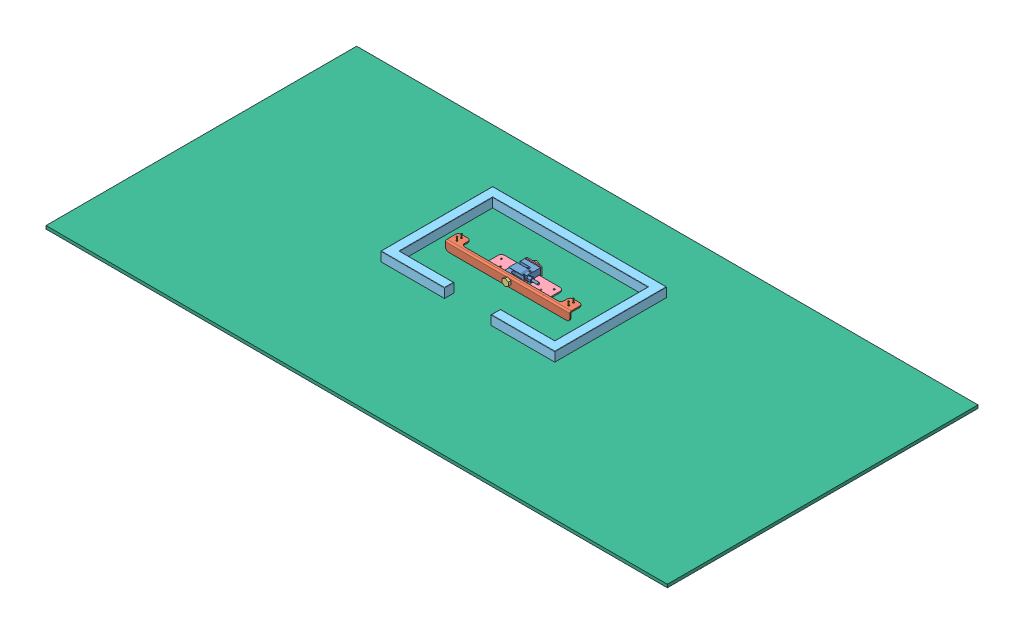
SolidWorks assembly WallBench - Assembly, configuration Default. Lengths in mm.
Overall size (2000 68.76 1000).
19 component instances, 9 part files, 39 mates.
Components (placement in the parent):
- WallBench - Galga-1: WallBench - Galga [Default] at (16.3505 77.3571 24.2126) size (82.8 24.7 76.5)
- WallBench - L Support-1: WallBench - L Support [Default] at (16.3505 104.6071 62.4626) x (1 0 0) z (0 1 0) size (400 41.44 29.24)
- Tornillo_M12-1: Tornillo_M12 [Default] at (16.3505 86.8571 -26.0374) x (0.845145 -0.534536 0) z (-0.534536 -0.845145 0) size (23.08 23 20.45)
- WallBench - Main Support-1: WallBench - Main Support [Default] at (16.3505 73.8571 24.1992) size (200 29.84 79.74)
- Tornillo_M12-2: Tornillo_M12 [Default] at (16.3505 86.8571 74.4626) x (0.885495 -0.464649 0) z (0.464649 0.885495 0) size (23.08 23 20.45)
- WallBench - Frame-1: WallBench - Frame [Default] at (21.3853 69.8571 19.8119) x (1 0 0) z (0 1 0) size (560 360 30)
- WallBench - Moving wall-1: WallBench - Moving wall [Default] at (20.7705 101.0937 20.8295) size (495 10 295) (hidden)
- Fingerboard-1: Fingerboard [Default] at (-181.7295 131.0937 22.8295) x (1 0 0) z (0 1 0) size (400 99 40) (hidden)
- Wall-1: Wall [Default] at (101.6517 59.8571 137.8054) size (2000 10 1000)
- din95_2_5x30_st-2: din95_2_5x30_st [Default] at (-68.6495 74.423 46.6992) x (-0.635709 0 -0.771929) z (0 -1 0) size (4.66 4.7 30.59)
- din95_2_5x30_st-3: din95_2_5x30_st [Default] at (-68.6495 74.423 1.6992) x (-0.635709 0 -0.771929) z (0 -1 0) size (4.66 4.7 30.59)
- din95_2_5x30_st-4: din95_2_5x30_st [Default] at (-48.6495 74.423 24.1992) x (-0.635709 0 -0.771929) z (0 -1 0) size (4.66 4.7 30.59)
- din95_2_5x30_st-5: din95_2_5x30_st [Default] at (101.3505 74.423 1.6992) x (-0.635709 0 -0.771929) z (0 -1 0) size (4.66 4.7 30.59)
- din95_2_5x30_st-6: din95_2_5x30_st [Default] at (81.3505 74.423 24.1992) x (-0.635709 0 -0.771929) z (0 -1 0) size (4.66 4.7 30.59)
- din95_2_5x30_st-7: din95_2_5x30_st [Default] at (101.3505 74.423 46.6992) x (-0.635709 0 -0.771929) z (0 -1 0) size (4.66 4.7 30.59)
- din95_2_5x30_st-8: din95_2_5x30_st [Default] at (196.3505 112.5937 35.0246) x (-0.899744 0 -0.436419) z (0 -1 0) size (4.66 4.7 30.59)
- din95_2_5x30_st-9: din95_2_5x30_st [Default] at (196.3505 112.5937 50.0246) x (-0.880156 0 0.474684) z (0 -1 0) size (4.66 4.7 30.59)
- din95_2_5x30_st-10: din95_2_5x30_st [Default] at (-163.6495 112.5937 35.0246) x (-0.080853 0 -0.996726) z (0 -1 0) size (4.66 4.7 30.59)
- din95_2_5x30_st-11: din95_2_5x30_st [Default] at (-163.6495 112.5937 50.0246) x (-0.159022 0 -0.987275) z (0 -1 0) size (4.66 4.7 30.59)
Mates (geometry in assembly coordinates):
- Concéntrica1: concentric anti-aligned: cylinder of WallBench - Galga-1 through (16.3505 86.8571 62.4636) axis (0 0 -1) radius 5; cylinder of WallBench - Main Support-1 through (16.3505 86.8571 -18.0384) axis (0 0 1) radius 7
- Coincidente2: coincident anti-aligned: plane of WallBench - Galga-1 through (-9.0495 96.3571 -14.0374) normal (0 0 -1); plane of WallBench - Main Support-1 through (-4.6495 94.695 -14.0374) normal (0 0 1)
- Concéntrica4: concentric aligned: cylinder of WallBench - Galga-1 through (16.3505 86.8571 62.4636) axis (0 0 -1) radius 5; cylinder of Tornillo_M12-1 through (16.3505 86.8571 -3.0374) axis (0 0 -1) radius 6
- Coincidente3: coincident anti-aligned: plane of Tornillo_M12-1 through (16.3505 86.8571 -18.0374) normal (0 0 1); plane of WallBench - Main Support-1 through (-4.6495 94.695 -18.0374) normal (0 0 -1)
- Perpendicular1: perpendicular: plane of Tornillo_M12-1 through (26.3505 81.0836 -18.0374) normal (1 0 0); plane of WallBench - Main Support-1 through (-4.6495 99.695 -18.0374) normal (0 1 0)
- Concéntrica5: concentric anti-aligned: cylinder of WallBench - Galga-1 through (16.3505 86.8571 -14.0384) axis (0 0 1) radius 5; cylinder of WallBench - L Support-1 through (16.3505 86.8571 72.4626) axis (0 0 -1) radius 7
- Coincidente4: coincident anti-aligned: plane of WallBench - Galga-1 through (-9.0495 96.3571 62.4626) normal (0 0 1); plane of WallBench - L Support-1 through (-173.6495 127.3571 62.4626) normal (0 0 -1)
- Paralelo1: parallel anti-aligned: plane of WallBench - Galga-1 through (10.7505 96.3571 42.4626) normal (0 1 0); plane of WallBench - L Support-1 through (-173.6495 97.0937 35.0246) normal (0 -1 0)
- Concéntrica7: concentric aligned: cylinder of WallBench - Galga-1 through (16.3505 86.8571 -14.0384) axis (0 0 1) radius 5; cylinder of Tornillo_M12-2 through (16.3505 86.8571 51.4626) axis (0 0 1) radius 6
- Coincidente6: coincident anti-aligned: plane of WallBench - L Support-1 through (-173.6495 127.3571 66.4626) normal (0 0 1); plane of Tornillo_M12-2 through (16.3505 86.8571 66.4626) normal (0 0 -1)
- Perpendicular2: perpendicular: plane of WallBench - L Support-1 through (-173.6495 101.0937 35.0246) normal (0 1 0); plane of Tornillo_M12-2 through (6.3505 81.0836 66.4626) normal (-1 0 0)
- Coincidente9: coincident anti-aligned: plane of WallBench - Frame-1 through (21.3853 69.8571 19.8119) normal (0 -1 0); plane of Wall-1 through (101.6517 69.8571 137.8054) normal (0 1 0)
- Coincidente13: coincident anti-aligned: plane of WallBench - Main Support-1 through (-4.6495 69.8571 -37.7008) normal (0 -1 0); plane of Wall-1 through (101.6517 69.8571 137.8054) normal (0 1 0)
- Paralelo5: parallel anti-aligned: plane of WallBench - L Support-1 through (-173.6495 127.3571 66.4626) normal (0 0 1); plane of WallBench - Frame-1 through (-228.6147 99.8571 169.8119) normal (0 0 -1)
- Coincidente15: coincident anti-aligned: plane of WallBench - Moving wall-1 through (20.7705 111.0937 20.8295) normal (0 1 0); plane of Fingerboard-1 through (218.2705 111.0937 72.3295) normal (0 -1 0)
- Distancia1: distance = 45 mm aligned: plane of Fingerboard-1 through (-181.7295 141.0937 -16.6705) normal (-1 0 0); plane of WallBench - Moving wall-1 through (-226.7295 111.0937 -126.6705) normal (-1 0 0)
- Distancia2: distance = 100 mm: plane of Fingerboard-1 through (218.2705 111.0937 -26.6705) normal (0 0 -1); line of WallBench - Moving wall-1 through (268.2705 101.0937 -126.6705) axis (-1 0 0)
- Coincidente19: coincident anti-aligned: plane of WallBench - L Support-1 through (-173.6495 101.0937 35.0246) normal (0 1 0); plane of WallBench - Moving wall-1 through (20.7705 101.0937 20.8295) normal (0 -1 0)
- Paralelo6: parallel aligned: plane of WallBench - Galga-1 through (10.7505 96.3571 42.4626) normal (0 1 0); plane of WallBench - Main Support-1 through (-4.6495 73.8571 -37.7008) normal (0 1 0)
- Concéntrica9: concentric aligned: cylinder of WallBench - Main Support-1 through (-68.6495 69.8561 1.6992) axis (0 1 0) radius 2.5; cylinder of din95_2_5x30_st-3 through (-68.6495 67.073 1.6992) axis (0 1 0) radius 1.25
- Concéntrica10: concentric aligned: cylinder of WallBench - Main Support-1 through (-48.6495 69.8561 24.1992) axis (0 1 0) radius 2.5; cylinder of din95_2_5x30_st-4 through (-48.6495 67.073 24.1992) axis (0 1 0) radius 1.25
- Concéntrica11: concentric aligned: cylinder of WallBench - Main Support-1 through (-68.6495 69.8561 46.6992) axis (0 1 0) radius 2.5; cylinder of din95_2_5x30_st-2 through (-68.6495 67.073 46.6992) axis (0 1 0) radius 1.25
- Concéntrica12: concentric aligned: cylinder of WallBench - Main Support-1 through (101.3505 69.8561 1.6992) axis (0 1 0) radius 2.5; cylinder of din95_2_5x30_st-5 through (101.3505 67.073 1.6992) axis (0 1 0) radius 1.25
- Concéntrica13: concentric aligned: cylinder of WallBench - Main Support-1 through (81.3505 69.8561 24.1992) axis (0 1 0) radius 2.5; cylinder of din95_2_5x30_st-6 through (81.3505 67.073 24.1992) axis (0 1 0) radius 1.25
- Concéntrica14: concentric aligned: cylinder of WallBench - Main Support-1 through (101.3505 69.8561 46.6992) axis (0 1 0) radius 2.5; cylinder of din95_2_5x30_st-7 through (101.3505 67.073 46.6992) axis (0 1 0) radius 1.25
- Coincidente22: coincident: circle of WallBench - Main Support-1; cone of din95_2_5x30_st-3 through (-68.6495 72.998 1.6992) axis (0 -1 0)
- Coincidente23: coincident: circle of WallBench - Main Support-1; cone of din95_2_5x30_st-4 through (-48.6495 72.998 24.1992) axis (0 -1 0); plane of ?
- Coincidente24: coincident: circle of WallBench - Main Support-1; cone of din95_2_5x30_st-2 through (-68.6495 72.998 46.6992) axis (0 -1 0); plane of ?
- Coincidente25: coincident: circle of WallBench - Main Support-1; cone of din95_2_5x30_st-7 through (101.3505 72.998 46.6992) axis (0 -1 0); plane of ?
- Coincidente26: coincident: circle of WallBench - Main Support-1; cone of din95_2_5x30_st-6 through (81.3505 72.998 24.1992) axis (0 -1 0); plane of ?
- Coincidente27: coincident: circle of WallBench - Main Support-1; cone of din95_2_5x30_st-5 through (101.3505 72.998 1.6992) axis (0 -1 0); plane of ?
- Concéntrica15: concentric anti-aligned: cylinder of WallBench - L Support-1 through (196.3505 101.0947 50.0246) axis (0 -1 0) radius 2.5; cylinder of din95_2_5x30_st-9 through (196.3505 105.2437 50.0246) axis (0 1 0) radius 1.25
- Concéntrica16: concentric anti-aligned: cylinder of WallBench - L Support-1 through (196.3505 101.0947 35.0246) axis (0 -1 0) radius 2.5; cylinder of din95_2_5x30_st-8 through (196.3505 105.2437 35.0246) axis (0 1 0) radius 1.25
- Concéntrica17: concentric anti-aligned: cylinder of WallBench - L Support-1 through (-163.6495 101.0947 35.0246) axis (0 -1 0) radius 2.5; cylinder of din95_2_5x30_st-10 through (-163.6495 105.2437 35.0246) axis (0 1 0) radius 1.25
- Concéntrica18: concentric anti-aligned: cylinder of WallBench - L Support-1 through (-163.6495 101.0947 50.0246) axis (0 -1 0) radius 2.5; cylinder of din95_2_5x30_st-11 through (-163.6495 105.2437 50.0246) axis (0 1 0) radius 1.25
- Distancia3: distance = 0.5 mm aligned: plane of din95_2_5x30_st-10 through (-163.6495 111.5937 35.0246) normal (0 1 0); plane of WallBench - Moving wall-1 through (20.7705 111.0937 20.8295) normal (0 1 0)
- Distancia4: distance = 0.5 mm aligned: plane of din95_2_5x30_st-11 through (-163.6495 111.5937 50.0246) normal (0 1 0); plane of WallBench - Moving wall-1 through (20.7705 111.0937 20.8295) normal (0 1 0)
- Distancia5: distance = 0.5 mm aligned: plane of din95_2_5x30_st-9 through (196.3505 111.5937 50.0246) normal (0 1 0); plane of WallBench - Moving wall-1 through (20.7705 111.0937 20.8295) normal (0 1 0)
- Distancia6: distance = 0.5 mm aligned: plane of din95_2_5x30_st-8 through (196.3505 111.5937 35.0246) normal (0 1 0); plane of WallBench - Moving wall-1 through (20.7705 111.0937 20.8295) normal (0 1 0)
